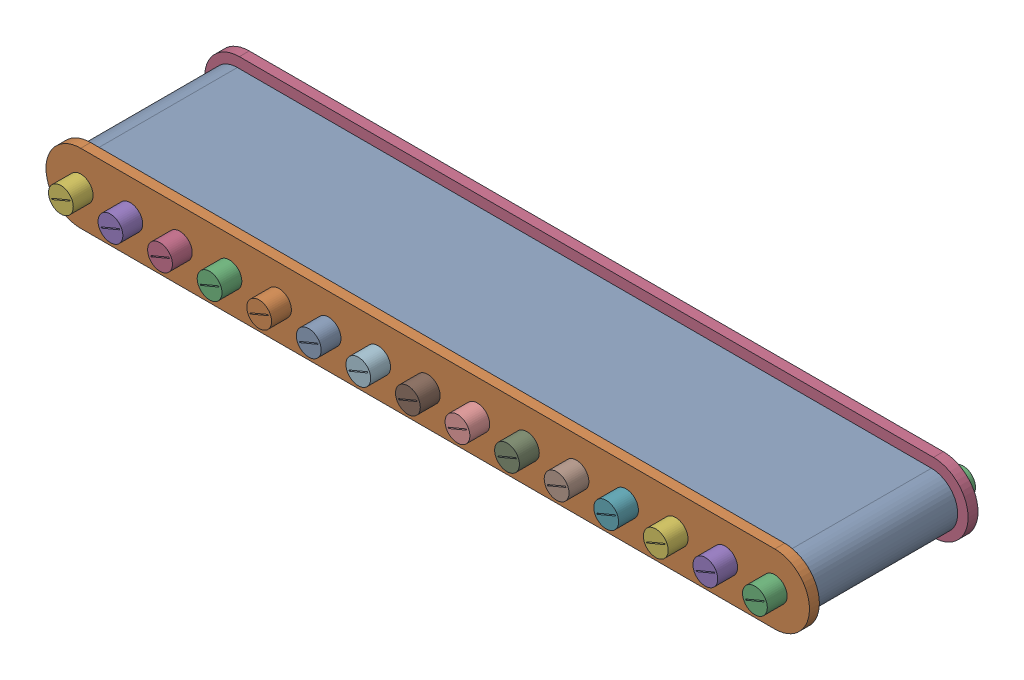
SolidWorks assembly FULL CONVEYOR 1, configuration Default. Lengths in mm.
Overall size (770 70 210).
18 component instances, 3 part files, 6 mates.
Components (placement in the parent):
- CONVEYOR-3: CONVEYOR [Default] at (-343.7007 225.4937 -62.3126) size (753 53 146)
- JOINT-5: JOINT [Default] at (-343.7007 225.4937 12.6874) size (770 70 10)
- ROLLER FOR CONVEYOR-51: ROLLER FOR CONVEYOR [Default] at (356.2993 225.4937 -62.3126) x (-0.386475 0.9223 0) z (0 0 1) size (50 50 210)
- JOINT-6: JOINT [Default] at (-343.7007 225.4937 -147.3126) size (770 70 10)
- ROLLER FOR CONVEYOR-52: ROLLER FOR CONVEYOR [Default] at (306.2993 225.4937 -62.3126) x (-0.386475 0.9223 0) z (0 0 1) size (50 50 210)
- ROLLER FOR CONVEYOR-53: ROLLER FOR CONVEYOR [Default] at (256.2993 225.4937 -62.3126) x (-0.386475 0.9223 0) z (0 0 1) size (50 50 210)
- ROLLER FOR CONVEYOR-54: ROLLER FOR CONVEYOR [Default] at (206.2993 225.4937 -62.3126) x (-0.386475 0.9223 0) z (0 0 1) size (50 50 210)
- ROLLER FOR CONVEYOR-55: ROLLER FOR CONVEYOR [Default] at (156.2993 225.4937 -62.3126) x (-0.386475 0.9223 0) z (0 0 1) size (50 50 210)
- ROLLER FOR CONVEYOR-56: ROLLER FOR CONVEYOR [Default] at (106.2993 225.4937 -62.3126) x (-0.386475 0.9223 0) z (0 0 1) size (50 50 210)
- ROLLER FOR CONVEYOR-57: ROLLER FOR CONVEYOR [Default] at (56.2993 225.4937 -62.3126) x (-0.386475 0.9223 0) z (0 0 1) size (50 50 210)
- ROLLER FOR CONVEYOR-58: ROLLER FOR CONVEYOR [Default] at (6.2993 225.4937 -62.3126) x (-0.386475 0.9223 0) z (0 0 1) size (50 50 210)
- ROLLER FOR CONVEYOR-59: ROLLER FOR CONVEYOR [Default] at (-43.7007 225.4937 -62.3126) x (-0.386475 0.9223 0) z (0 0 1) size (50 50 210)
- ROLLER FOR CONVEYOR-60: ROLLER FOR CONVEYOR [Default] at (-93.7007 225.4937 -62.3126) x (-0.386475 0.9223 0) z (0 0 1) size (50 50 210)
- ROLLER FOR CONVEYOR-61: ROLLER FOR CONVEYOR [Default] at (-143.7007 225.4937 -62.3126) x (-0.386475 0.9223 0) z (0 0 1) size (50 50 210)
- ROLLER FOR CONVEYOR-62: ROLLER FOR CONVEYOR [Default] at (-193.7007 225.4937 -62.3126) x (-0.386475 0.9223 0) z (0 0 1) size (50 50 210)
- ROLLER FOR CONVEYOR-63: ROLLER FOR CONVEYOR [Default] at (-243.7007 225.4937 -62.3126) x (-0.386475 0.9223 0) z (0 0 1) size (50 50 210)
- ROLLER FOR CONVEYOR-64: ROLLER FOR CONVEYOR [Default] at (-293.7007 225.4937 -62.3126) x (-0.386475 0.9223 0) z (0 0 1) size (50 50 210)
- ROLLER FOR CONVEYOR-65: ROLLER FOR CONVEYOR [Default] at (-343.7007 225.4937 -62.3126) x (-0.386475 0.9223 0) z (0 0 1) size (50 50 210)
Mates (geometry in assembly coordinates):
- Coincident10: coincident aligned: circle of JOINT-5; circle of ROLLER FOR CONVEYOR-51
- Coincident11: coincident aligned: circle of ROLLER FOR CONVEYOR-51; circle of JOINT-6
- Concentric5: concentric aligned: circle of CONVEYOR-3; circle of JOINT-6
- Concentric6: concentric aligned: circle of CONVEYOR-3; circle of JOINT-5
- Coincident13: coincident anti-aligned: circle of CONVEYOR-3; circle of ROLLER FOR CONVEYOR-65
- Coincident14: coincident aligned: circle of JOINT-6; circle of ROLLER FOR CONVEYOR-65
